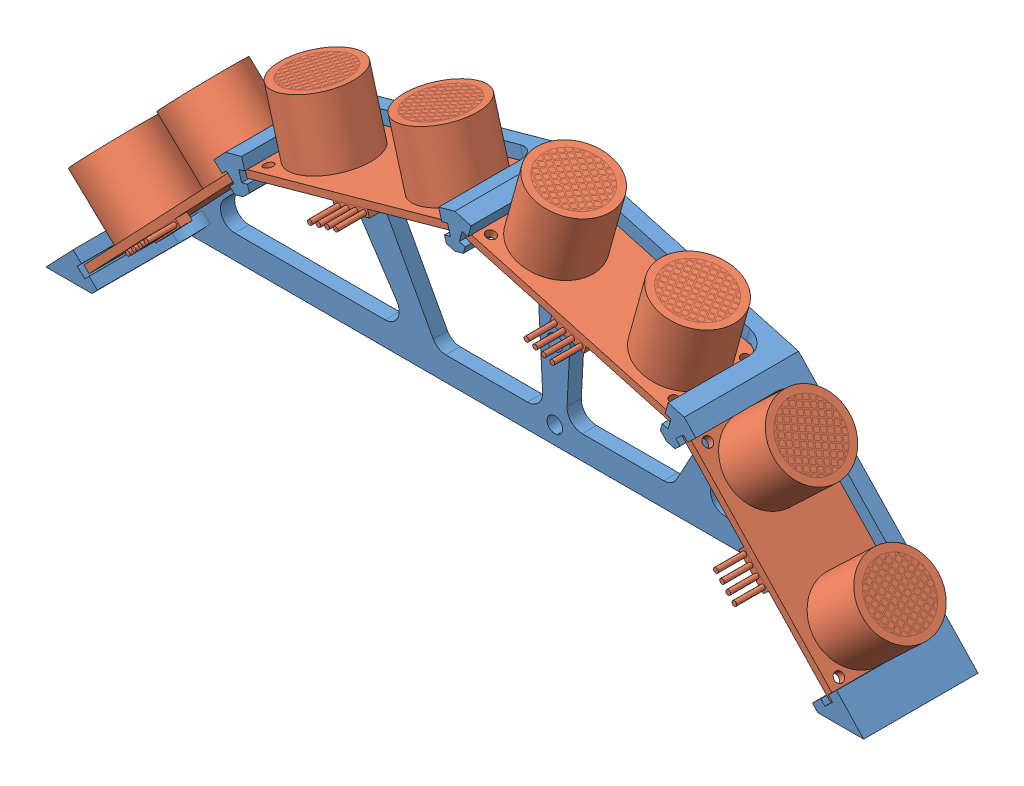
SolidWorks assembly Ultrasonic _array, configuration Default. Lengths in mm.
Overall size (177.35 62.76 29).
5 component instances, 2 part files, 12 mates.
Components (placement in the parent):
- 120_deg_ultrasonic_sensor_mount-1: 120_deg_ultrasonic_sensor_mount [Default] at (-29.2897 -6.8968 -5.6084) size (171.73 53.07 24)
- Ultrasonic-1: Ultrasonic [Default] at (33.874 5.6509 5.8916) x (-0.688355 0.725374 0) z (0.725374 0.688355 0) size (45 26 16.5)
- Ultrasonic-2: Ultrasonic [Default] at (-5.7012 29.7095 5.8916) x (-0.96363 0.267238 0) z (0.267238 0.96363 0) size (45 26 16.5)
- Ultrasonic-3: Ultrasonic [Default] at (-52.0148 29.9489 5.8916) x (-0.96363 -0.267238 0) z (-0.267238 0.96363 0) size (45 26 16.5)
- Ultrasonic-4: Ultrasonic [Default] at (-91.8366 6.3009 5.8916) x (-0.688355 -0.725374 0) z (-0.725374 0.688355 0) size (45 26 16.5)
Mates (geometry in assembly coordinates):
- Coincident6: coincident anti-aligned: plane of 120_deg_ultrasonic_sensor_mount-1 through (-29.2897 -6.8968 -2.6084) normal (0 0 1); plane of Ultrasonic-1 through (48.5058 -10.8648 -2.6084) normal (0 0 -1)
- Width1: width aligned: plane of 120_deg_ultrasonic_sensor_mount-1 through (9.7256 -48.0104 18.3916) normal (-0.688355 0.725374 0); plane of 120_deg_ultrasonic_sensor_mount-1 through (-21.5945 -15.0059 18.3916) normal (0.688355 -0.725374 0); plane of Ultrasonic-1 through (17.5298 21.7771 -2.6084) normal (-0.688355 0.725374 0); plane of Ultrasonic-1 through (48.5058 -10.8648 17.3916) normal (0.688355 -0.725374 0)
- Width2: width anti-aligned: plane of 120_deg_ultrasonic_sensor_mount-1 through (11.0045 31.3409 18.3916) normal (-0.725374 -0.688355 0); plane of 120_deg_ultrasonic_sensor_mount-1 through (9.4086 29.8266 18.3916) normal (0.725374 0.688355 0); plane of Ultrasonic-1 through (34.1059 6.4887 7.3916) normal (0.725374 0.688355 0); plane of Ultrasonic-1 through (33.0178 5.4561 7.3916) normal (-0.725374 -0.688355 0)
- Coincident7: coincident anti-aligned: plane of 120_deg_ultrasonic_sensor_mount-1 through (-29.2897 -6.8968 -2.6084) normal (0 0 1); plane of Ultrasonic-2 through (15.347 23.0887 -2.6084) normal (0 0 -1)
- Width4: width anti-aligned: plane of Ultrasonic-2 through (-28.0164 35.1144 -2.6084) normal (-0.96363 0.267238 0); plane of Ultrasonic-2 through (15.347 23.0887 17.3916) normal (0.96363 -0.267238 0); plane of 120_deg_ultrasonic_sensor_mount-1 through (-39.1669 -4.1576 18.3916) normal (0.96363 -0.267238 0); plane of 120_deg_ultrasonic_sensor_mount-1 through (4.6782 -16.317 18.3916) normal (-0.96363 0.267238 0)
- Width5: width anti-aligned: plane of Ultrasonic-2 through (-5.9339 30.547 7.3916) normal (0.267238 0.96363 0); plane of Ultrasonic-2 through (-6.3347 29.1015 7.3916) normal (-0.267238 -0.96363 0); plane of 120_deg_ultrasonic_sensor_mount-1 through (-17.8857 34.2247 18.3916) normal (-0.267238 -0.96363 0); plane of 120_deg_ultrasonic_sensor_mount-1 through (-18.4736 32.1047 18.3916) normal (0.267238 0.96363 0)
- Coincident8: coincident anti-aligned: plane of 120_deg_ultrasonic_sensor_mount-1 through (-29.2897 -6.8968 -2.6084) normal (0 0 1); plane of Ultrasonic-3 through (-30.563 35.1144 -2.6084) normal (0 0 -1)
- Width6: width anti-aligned: plane of Ultrasonic-3 through (-52.6456 30.547 7.3916) normal (-0.267238 0.96363 0); plane of Ultrasonic-3 through (-52.2447 29.1015 7.3916) normal (0.267238 -0.96363 0); plane of 120_deg_ultrasonic_sensor_mount-1 through (-40.6937 34.2247 18.3916) normal (0.267238 -0.96363 0); plane of 120_deg_ultrasonic_sensor_mount-1 through (-40.1058 32.1047 18.3916) normal (-0.267238 0.96363 0)
- Width7: width anti-aligned: plane of Ultrasonic-3 through (-30.563 35.1144 17.3916) normal (0.96363 0.267238 0); plane of Ultrasonic-3 through (-73.9264 23.0887 -2.6084) normal (-0.96363 -0.267238 0); plane of 120_deg_ultrasonic_sensor_mount-1 through (-19.4125 -4.1576 18.3916) normal (-0.96363 -0.267238 0); plane of 120_deg_ultrasonic_sensor_mount-1 through (-63.2577 -16.317 18.3916) normal (0.96363 0.267238 0)
- Coincident9: coincident anti-aligned: plane of 120_deg_ultrasonic_sensor_mount-1 through (-29.2897 -6.8968 -2.6084) normal (0 0 1); plane of Ultrasonic-4 through (-76.1093 21.7771 -2.6084) normal (0 0 -1)
- Width8: width aligned: plane of Ultrasonic-4 through (-91.5973 5.4561 7.3916) normal (0.725374 -0.688355 0); plane of Ultrasonic-4 through (-92.6853 6.4887 7.3916) normal (-0.725374 0.688355 0); plane of 120_deg_ultrasonic_sensor_mount-1 through (-69.5839 31.3409 18.3916) normal (0.725374 -0.688355 0); plane of 120_deg_ultrasonic_sensor_mount-1 through (-67.9881 29.8266 18.3916) normal (-0.725374 0.688355 0)
- Width9: width anti-aligned: plane of Ultrasonic-4 through (-76.1093 21.7771 17.3916) normal (0.688355 0.725374 0); plane of Ultrasonic-4 through (-107.0853 -10.8648 -2.6084) normal (-0.688355 -0.725374 0); plane of 120_deg_ultrasonic_sensor_mount-1 through (-36.985 -15.0059 18.3916) normal (-0.688355 -0.725374 0); plane of 120_deg_ultrasonic_sensor_mount-1 through (-68.3051 -48.0104 18.3916) normal (0.688355 0.725374 0)
